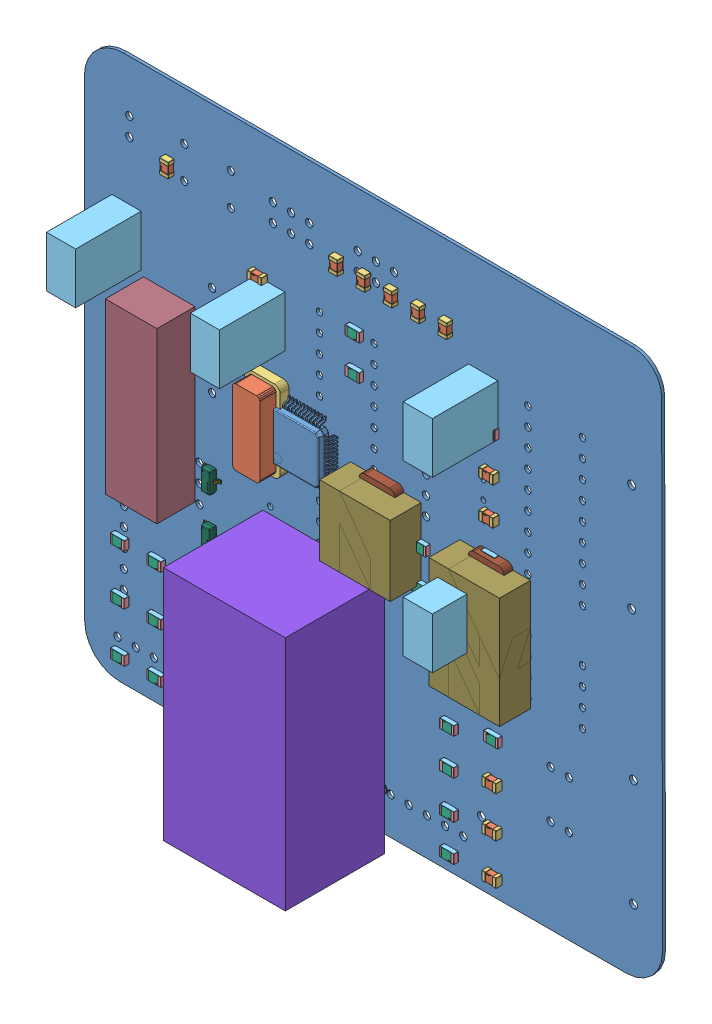
SolidWorks assembly VTM Ethernet Module.step, configuration Default. Lengths in mm.
Overall size (80.69 78.46 18.97).
296 component instances, 25 part files, 0 mates.
Components (placement in the parent):
- Board.step-1: Board.step [Default] at origin size (80.69 76.24 0.41)
  - Open CASCADE STEP translator 7.5 1.1.1.step-1: Open CASCADE STEP translator 7.5 1.1.1.step [Default] at (0 0 -0.4115) size (80.69 76.24 0.41)
- Y1.step-1: Y1.step [Default] at origin size (5 11.35 3.5)
  - 6024891824.step-1: 6024891824.step [Default] at (26.035 42.291 0) size (3.8 10.5 3.5)
    - Extruded.step-1: Extruded.step [Default] at origin size (3.8 10.5 3.5)
  - 6024891904.step-1: 6024891904.step [Default] at (26.035 42.291 0) size (5 11.35 1.25)
    - Extruded-0.step-1: Extruded-0.step [Default] at origin size (5 11.35 1.25)
- RY.step-1: RY.step [Default] at origin size (2 1.25 0.65)
  - Res_TE_Connectivity_CPF0805B66R5E1_eec.step-1: Res_TE_Connectivity_CPF0805B66R5E1_eec.step [Default] at (51.169 17.907 0) size (2 1.25 0.65)
    - 1.step-1: 1.step [Default] at origin size (2 1.25 0.65)
    - 2.step-1: 2.step [Default] at origin size (1.92 1.25 0.61)
    - 3.step-1: 3.step [Default] at origin size (1.3 1.25 0.04)
    - TE connectivity Logo 1 (2).step-1: TE connectivity Logo 1 (2).step [Default] at (5.4285 0.313 0.551) x (-1 0 0) z (0 0 1) size (0.37 0.13 0.11)
- RLL5.step-1: RLL5.step [Default] at origin size (2 1.25 0.65)
  - Res_TE_Connectivity_CPF0805B66R5E1_eec.step-1: Res_TE_Connectivity_CPF0805B66R5E1_eec.step [Default] at (10.287 3.368 0) x (-1 0 0) z (0 0 1) size (2 1.25 0.65)
    - 1.step-1: 1.step [Default] at origin size (2 1.25 0.65)
    - 2.step-1: 2.step [Default] at origin size (1.92 1.25 0.61)
    - 3.step-1: 3.step [Default] at origin size (1.3 1.25 0.04)
    - TE connectivity Logo 1 (2).step-1: TE connectivity Logo 1 (2).step [Default] at (5.4285 0.313 0.551) x (-1 0 0) z (0 0 1) size (0.37 0.13 0.11)
- RLL4.step-1: RLL4.step [Default] at origin size (2 1.25 0.65)
  - Res_TE_Connectivity_CPF0805B66R5E1_eec.step-1: Res_TE_Connectivity_CPF0805B66R5E1_eec.step [Default] at (10.287 10.287 0) x (-1 0 0) z (0 0 1) size (2 1.25 0.65)
    - 1.step-1: 1.step [Default] at origin size (2 1.25 0.65)
    - 2.step-1: 2.step [Default] at origin size (1.92 1.25 0.61)
    - 3.step-1: 3.step [Default] at origin size (1.3 1.25 0.04)
    - TE connectivity Logo 1 (2).step-1: TE connectivity Logo 1 (2).step [Default] at (5.4285 0.313 0.551) x (-1 0 0) z (0 0 1) size (0.37 0.13 0.11)
- RLL3.step-1: RLL3.step [Default] at origin size (2 1.25 0.65)
  - Res_TE_Connectivity_CPF0805B66R5E1_eec.step-1: Res_TE_Connectivity_CPF0805B66R5E1_eec.step [Default] at (10.287 17.272 0) x (-1 0 0) z (0 0 1) size (2 1.25 0.65)
    - 1.step-1: 1.step [Default] at origin size (2 1.25 0.65)
    - 2.step-1: 2.step [Default] at origin size (1.92 1.25 0.61)
    - 3.step-1: 3.step [Default] at origin size (1.3 1.25 0.04)
    - TE connectivity Logo 1 (2).step-1: TE connectivity Logo 1 (2).step [Default] at (5.4285 0.313 0.551) x (-1 0 0) z (0 0 1) size (0.37 0.13 0.11)
- RLL2.step-1: RLL2.step [Default] at origin size (2 1.25 0.65)
  - Res_TE_Connectivity_CPF0805B66R5E1_eec.step-1: Res_TE_Connectivity_CPF0805B66R5E1_eec.step [Default] at (10.287 24.257 0) x (-1 0 0) z (0 0 1) size (2 1.25 0.65)
    - 1.step-1: 1.step [Default] at origin size (2 1.25 0.65)
    - 2.step-1: 2.step [Default] at origin size (1.92 1.25 0.61)
    - 3.step-1: 3.step [Default] at origin size (1.3 1.25 0.04)
    - TE connectivity Logo 1 (2).step-1: TE connectivity Logo 1 (2).step [Default] at (5.4285 0.313 0.551) x (-1 0 0) z (0 0 1) size (0.37 0.13 0.11)
- RLL1.step-1: RLL1.step [Default] at origin size (2 1.25 0.65)
  - Res_TE_Connectivity_CPF0805B66R5E1_eec.step-1: Res_TE_Connectivity_CPF0805B66R5E1_eec.step [Default] at (10.287 31.181 0) x (-1 0 0) z (0 0 1) size (2 1.25 0.65)
    - 1.step-1: 1.step [Default] at origin size (2 1.25 0.65)
    - 2.step-1: 2.step [Default] at origin size (1.92 1.25 0.61)
    - 3.step-1: 3.step [Default] at origin size (1.3 1.25 0.04)
    - TE connectivity Logo 1 (2).step-1: TE connectivity Logo 1 (2).step [Default] at (5.4285 0.313 0.551) x (-1 0 0) z (0 0 1) size (0.37 0.13 0.11)
- RLH5.step-1: RLH5.step [Default] at origin size (2 1.25 0.65)
  - Res_TE_Connectivity_CPF0805B66R5E1_eec.step-1: Res_TE_Connectivity_CPF0805B66R5E1_eec.step [Default] at (5.191 3.368 0) x (-1 0 0) z (0 0 1) size (2 1.25 0.65)
    - 1.step-1: 1.step [Default] at origin size (2 1.25 0.65)
    - 2.step-1: 2.step [Default] at origin size (1.92 1.25 0.61)
    - 3.step-1: 3.step [Default] at origin size (1.3 1.25 0.04)
    - TE connectivity Logo 1 (2).step-1: TE connectivity Logo 1 (2).step [Default] at (5.4285 0.313 0.551) x (-1 0 0) z (0 0 1) size (0.37 0.13 0.11)
- RLH4.step-1: RLH4.step [Default] at origin size (2 1.25 0.65)
  - Res_TE_Connectivity_CPF0805B66R5E1_eec.step-1: Res_TE_Connectivity_CPF0805B66R5E1_eec.step [Default] at (5.191 10.287 0) x (-1 0 0) z (0 0 1) size (2 1.25 0.65)
    - 1.step-1: 1.step [Default] at origin size (2 1.25 0.65)
    - 2.step-1: 2.step [Default] at origin size (1.92 1.25 0.61)
    - 3.step-1: 3.step [Default] at origin size (1.3 1.25 0.04)
    - TE connectivity Logo 1 (2).step-1: TE connectivity Logo 1 (2).step [Default] at (5.4285 0.313 0.551) x (-1 0 0) z (0 0 1) size (0.37 0.13 0.11)
- RLH3.step-1: RLH3.step [Default] at origin size (2 1.25 0.65)
  - Res_TE_Connectivity_CPF0805B66R5E1_eec.step-1: Res_TE_Connectivity_CPF0805B66R5E1_eec.step [Default] at (5.191 17.272 0) x (-1 0 0) z (0 0 1) size (2 1.25 0.65)
    - 1.step-1: 1.step [Default] at origin size (2 1.25 0.65)
    - 2.step-1: 2.step [Default] at origin size (1.92 1.25 0.61)
    - 3.step-1: 3.step [Default] at origin size (1.3 1.25 0.04)
    - TE connectivity Logo 1 (2).step-1: TE connectivity Logo 1 (2).step [Default] at (5.4285 0.313 0.551) x (-1 0 0) z (0 0 1) size (0.37 0.13 0.11)
- RLH2.step-1: RLH2.step [Default] at origin size (2 1.25 0.65)
  - Res_TE_Connectivity_CPF0805B66R5E1_eec.step-1: Res_TE_Connectivity_CPF0805B66R5E1_eec.step [Default] at (5.191 24.257 0) x (-1 0 0) z (0 0 1) size (2 1.25 0.65)
    - 1.step-1: 1.step [Default] at origin size (2 1.25 0.65)
    - 2.step-1: 2.step [Default] at origin size (1.92 1.25 0.61)
    - 3.step-1: 3.step [Default] at origin size (1.3 1.25 0.04)
    - TE connectivity Logo 1 (2).step-1: TE connectivity Logo 1 (2).step [Default] at (5.4285 0.313 0.551) x (-1 0 0) z (0 0 1) size (0.37 0.13 0.11)
- RLH1.step-1: RLH1.step [Default] at origin size (2 1.25 0.65)
  - Res_TE_Connectivity_CPF0805B66R5E1_eec.step-1: Res_TE_Connectivity_CPF0805B66R5E1_eec.step [Default] at (5.191 31.181 0) x (-1 0 0) z (0 0 1) size (2 1.25 0.65)
    - 1.step-1: 1.step [Default] at origin size (2 1.25 0.65)
    - 2.step-1: 2.step [Default] at origin size (1.92 1.25 0.61)
    - 3.step-1: 3.step [Default] at origin size (1.3 1.25 0.04)
    - TE connectivity Logo 1 (2).step-1: TE connectivity Logo 1 (2).step [Default] at (5.4285 0.313 0.551) x (-1 0 0) z (0 0 1) size (0.37 0.13 0.11)
- RJ45.step-1: RJ45.step [Default] at origin size (17.5 33.02 18.97)
  - 6024909664.step-1: 6024909664.step [Default] at (38.539 23.881 0) x (1 0 0) z (0 0 1) size (17.5 33.02 18.97)
    - Body.step-1: Body.step [Default] at (0 0 0.1) size (17 33.02 13.87)
    - Lugs.step-1: Lugs.step [Default] at origin size (15.3 2.6 1.8)
    - Leads.step-1: Leads.step [Default] at origin size (17.5 24.59 5.1)
- RG.step-1: RG.step [Default] at origin size (2 1.25 0.65)
  - Res_TE_Connectivity_CPF0805B66R5E1_eec.step-1: Res_TE_Connectivity_CPF0805B66R5E1_eec.step [Default] at (51.153 12.827 0) size (2 1.25 0.65)
    - 1.step-1: 1.step [Default] at origin size (2 1.25 0.65)
    - 2.step-1: 2.step [Default] at origin size (1.92 1.25 0.61)
    - 3.step-1: 3.step [Default] at origin size (1.3 1.25 0.04)
    - TE connectivity Logo 1 (2).step-1: TE connectivity Logo 1 (2).step [Default] at (5.4285 0.313 0.551) x (-1 0 0) z (0 0 1) size (0.37 0.13 0.11)
- R_MH4.step-1: R_MH4.step [Default] at origin size (2 1.25 0.65)
  - Res_TE_Connectivity_CPF0805B66R5E1_eec.step-1: Res_TE_Connectivity_CPF0805B66R5E1_eec.step [Default] at (51.169 7.493 0) x (-1 0 0) z (0 0 1) size (2 1.25 0.65)
    - 1.step-1: 1.step [Default] at origin size (2 1.25 0.65)
    - 2.step-1: 2.step [Default] at origin size (1.92 1.25 0.61)
    - 3.step-1: 3.step [Default] at origin size (1.3 1.25 0.04)
    - TE connectivity Logo 1 (2).step-1: TE connectivity Logo 1 (2).step [Default] at (5.4285 0.313 0.551) x (-1 0 0) z (0 0 1) size (0.37 0.13 0.11)
- R_MH3.step-1: R_MH3.step [Default] at origin size (2 1.25 0.65)
  - Res_TE_Connectivity_CPF0805B66R5E1_eec.step-1: Res_TE_Connectivity_CPF0805B66R5E1_eec.step [Default] at (51.169 2.413 0) x (-1 0 0) z (0 0 1) size (2 1.25 0.65)
    - 1.step-1: 1.step [Default] at origin size (2 1.25 0.65)
    - 2.step-1: 2.step [Default] at origin size (1.92 1.25 0.61)
    - 3.step-1: 3.step [Default] at origin size (1.3 1.25 0.04)
    - TE connectivity Logo 1 (2).step-1: TE connectivity Logo 1 (2).step [Default] at (5.4285 0.313 0.551) x (-1 0 0) z (0 0 1) size (0.37 0.13 0.11)
- R15.step-1: R15.step [Default] at origin size (2 1.25 0.65)
  - Res_TE_Connectivity_CPF0805B66R5E1_eec.step-1: Res_TE_Connectivity_CPF0805B66R5E1_eec.step [Default] at (56.841 41.021 0) size (2 1.25 0.65)
    - 1.step-1: 1.step [Default] at origin size (2 1.25 0.65)
    - 2.step-1: 2.step [Default] at origin size (1.92 1.25 0.61)
    - 3.step-1: 3.step [Default] at origin size (1.3 1.25 0.04)
    - TE connectivity Logo 1 (2).step-1: TE connectivity Logo 1 (2).step [Default] at (5.4285 0.313 0.551) x (-1 0 0) z (0 0 1) size (0.37 0.13 0.11)
- R14.step-1: R14.step [Default] at origin size (2 1.25 0.65)
  - Res_TE_Connectivity_CPF0805B66R5E1_eec.step-1: Res_TE_Connectivity_CPF0805B66R5E1_eec.step [Default] at (37.973 58.828 0) x (-1 0 0) z (0 0 1) size (2 1.25 0.65)
    - 1.step-1: 1.step [Default] at origin size (2 1.25 0.65)
    - 2.step-1: 2.step [Default] at origin size (1.92 1.25 0.61)
    - 3.step-1: 3.step [Default] at origin size (1.3 1.25 0.04)
    - TE connectivity Logo 1 (2).step-1: TE connectivity Logo 1 (2).step [Default] at (5.4285 0.313 0.551) x (-1 0 0) z (0 0 1) size (0.37 0.13 0.11)
- R13.step-1: R13.step [Default] at origin size (2 1.25 0.65)
  - Res_TE_Connectivity_CPF0805B66R5E1_eec.step-1: Res_TE_Connectivity_CPF0805B66R5E1_eec.step [Default] at (37.973 53.948 0) x (1 0 0) z (0 0 1) size (2 1.25 0.65)
    - 1.step-1: 1.step [Default] at origin size (2 1.25 0.65)
    - 2.step-1: 2.step [Default] at origin size (1.92 1.25 0.61)
    - 3.step-1: 3.step [Default] at origin size (1.3 1.25 0.04)
    - TE connectivity Logo 1 (2).step-1: TE connectivity Logo 1 (2).step [Default] at (5.4285 0.313 0.551) x (-1 0 0) z (0 0 1) size (0.37 0.13 0.11)
- R12.step-1: R12.step [Default] at origin size (2 1.25 0.65)
  - Res_TE_Connectivity_CPF0805B66R5E1_eec.step-1: Res_TE_Connectivity_CPF0805B66R5E1_eec.step [Default] at (57.277 19.431 0) size (2 1.25 0.65)
    - 1.step-1: 1.step [Default] at origin size (2 1.25 0.65)
    - 2.step-1: 2.step [Default] at origin size (1.92 1.25 0.61)
    - 3.step-1: 3.step [Default] at origin size (1.3 1.25 0.04)
    - TE connectivity Logo 1 (2).step-1: TE connectivity Logo 1 (2).step [Default] at (5.4285 0.313 0.551) x (-1 0 0) z (0 0 1) size (0.37 0.13 0.11)
- R11.step-1: R11.step [Default] at origin size (2 1.25 0.65)
  - Res_TE_Connectivity_CPF0805B66R5E1_eec.step-1: Res_TE_Connectivity_CPF0805B66R5E1_eec.step [Default] at (57.277 24.511 0) size (2 1.25 0.65)
    - 1.step-1: 1.step [Default] at origin size (2 1.25 0.65)
    - 2.step-1: 2.step [Default] at origin size (1.92 1.25 0.61)
    - 3.step-1: 3.step [Default] at origin size (1.3 1.25 0.04)
    - TE connectivity Logo 1 (2).step-1: TE connectivity Logo 1 (2).step [Default] at (5.4285 0.313 0.551) x (-1 0 0) z (0 0 1) size (0.37 0.13 0.11)
- R10.step-1: R10.step [Default] at origin size (9.85 11.35 4.32)
  - 6024890784.step-1: 6024890784.step [Default] at (57.277 30.226 0) size (5 11.35 1.25)
    - Extruded-1.step-1: Extruded-1.step [Default] at origin size (5 11.35 1.25)
  - 6024891024.step-1: 6024891024.step [Default] at (55.902 30.226 0) size (7.1 9.8 4.32)
    - Extruded-2.step-1: Extruded-2.step [Default] at origin size (7.1 9.8 4.32)
  - 6024891024.step-2: 6024891024.step [Default] at (58.652 30.226 0) size (7.1 9.8 4.32)
    - Extruded-2.step-1: Extruded-2.step [Default] at origin size (7.1 9.8 4.32)
- R9.step-1: R9.step [Default] at origin size (9.85 11.35 4.32)
  - 6024891024.step-1: 6024891024.step [Default] at (58.652 35.941 0) size (7.1 9.8 4.32)
    - Extruded-2.step-1: Extruded-2.step [Default] at origin size (7.1 9.8 4.32)
  - 6024891024.step-2: 6024891024.step [Default] at (55.902 35.941 0) size (7.1 9.8 4.32)
    - Extruded-2.step-1: Extruded-2.step [Default] at origin size (7.1 9.8 4.32)
  - 6024890784.step-1: 6024890784.step [Default] at (57.277 35.941 0) size (5 11.35 1.25)
    - Extruded-1.step-1: Extruded-1.step [Default] at origin size (5 11.35 1.25)
- R8.step-1: R8.step [Default] at origin size (7.2 23.6 5.33)
  - 6024888544.step-1: 6024888544.step [Default] at (11.811 38.735 0) size (7.2 23.6 5.33)
    - Extruded-3.step-1: Extruded-3.step [Default] at origin size (7.2 23.6 5.33)
  - 6024888384.step-1: 6024888384.step [Default] at (11.811 40.11 0) size (1.65 0.5 0.7)
    - Extruded-4.step-1: Extruded-4.step [Default] at origin size (1.65 0.5 0.7)
  - 6024888384.step-2: 6024888384.step [Default] at (11.811 37.36 0) size (1.65 0.5 0.7)
    - Extruded-4.step-1: Extruded-4.step [Default] at origin size (1.65 0.5 0.7)
- R7.step-1: R7.step [Default] at origin size (9.85 11.35 4.32)
  - 6024890784.step-1: 6024890784.step [Default] at (42.037 37.719 0) size (5 11.35 1.25)
    - Extruded-1.step-1: Extruded-1.step [Default] at origin size (5 11.35 1.25)
  - 6024891024.step-1: 6024891024.step [Default] at (40.662 37.719 0) size (7.1 9.8 4.32)
    - Extruded-2.step-1: Extruded-2.step [Default] at origin size (7.1 9.8 4.32)
  - 6024891024.step-2: 6024891024.step [Default] at (43.412 37.719 0) size (7.1 9.8 4.32)
    - Extruded-2.step-1: Extruded-2.step [Default] at origin size (7.1 9.8 4.32)
- R6.step-1: R6.step [Default] at origin size (2 1.25 0.65)
  - Res_TE_Connectivity_CPF0805B66R5E1_eec.step-1: Res_TE_Connectivity_CPF0805B66R5E1_eec.step [Default] at (56.841 56.388 0) size (2 1.25 0.65)
    - 1.step-1: 1.step [Default] at origin size (2 1.25 0.65)
    - 2.step-1: 2.step [Default] at origin size (1.92 1.25 0.61)
    - 3.step-1: 3.step [Default] at origin size (1.3 1.25 0.04)
    - TE connectivity Logo 1 (2).step-1: TE connectivity Logo 1 (2).step [Default] at (5.4285 0.313 0.551) x (-1 0 0) z (0 0 1) size (0.37 0.13 0.11)
- R5.step-1: R5.step [Default] at origin size (2 1.25 0.65)
  - Res_TE_Connectivity_CPF0805B66R5E1_eec.step-1: Res_TE_Connectivity_CPF0805B66R5E1_eec.step [Default] at (47.244 37.592 0) size (2 1.25 0.65)
    - 1.step-1: 1.step [Default] at origin size (2 1.25 0.65)
    - 2.step-1: 2.step [Default] at origin size (1.92 1.25 0.61)
    - 3.step-1: 3.step [Default] at origin size (1.3 1.25 0.04)
    - TE connectivity Logo 1 (2).step-1: TE connectivity Logo 1 (2).step [Default] at (5.4285 0.313 0.551) x (-1 0 0) z (0 0 1) size (0.37 0.13 0.11)
- R4.step-1: R4.step [Default] at origin size (2 1.25 0.65)
  - Res_TE_Connectivity_CPF0805B66R5E1_eec.step-1: Res_TE_Connectivity_CPF0805B66R5E1_eec.step [Default] at (51.169 22.987 0) size (2 1.25 0.65)
    - 1.step-1: 1.step [Default] at origin size (2 1.25 0.65)
    - 2.step-1: 2.step [Default] at origin size (1.92 1.25 0.61)
    - 3.step-1: 3.step [Default] at origin size (1.3 1.25 0.04)
    - TE connectivity Logo 1 (2).step-1: TE connectivity Logo 1 (2).step [Default] at (5.4285 0.313 0.551) x (-1 0 0) z (0 0 1) size (0.37 0.13 0.11)
- R3.step-1: R3.step [Default] at origin size (2 1.25 0.65)
  - Res_TE_Connectivity_CPF0805B66R5E1_eec.step-1: Res_TE_Connectivity_CPF0805B66R5E1_eec.step [Default] at (47.117 32.639 0) x (-1 0 0) z (0 0 1) size (2 1.25 0.65)
    - 1.step-1: 1.step [Default] at origin size (2 1.25 0.65)
    - 2.step-1: 2.step [Default] at origin size (1.92 1.25 0.61)
    - 3.step-1: 3.step [Default] at origin size (1.3 1.25 0.04)
    - TE connectivity Logo 1 (2).step-1: TE connectivity Logo 1 (2).step [Default] at (5.4285 0.313 0.551) x (-1 0 0) z (0 0 1) size (0.37 0.13 0.11)
- R2.step-1: R2.step [Default] at origin size (2 1.25 0.65)
  - Res_TE_Connectivity_CPF0805B66R5E1_eec.step-1: Res_TE_Connectivity_CPF0805B66R5E1_eec.step [Default] at (42.037 32.512 0) size (2 1.25 0.65)
    - 1.step-1: 1.step [Default] at origin size (2 1.25 0.65)
    - 2.step-1: 2.step [Default] at origin size (1.92 1.25 0.61)
    - 3.step-1: 3.step [Default] at origin size (1.3 1.25 0.04)
    - TE connectivity Logo 1 (2).step-1: TE connectivity Logo 1 (2).step [Default] at (5.4285 0.313 0.551) x (-1 0 0) z (0 0 1) size (0.37 0.13 0.11)
- R1.step-1: R1.step [Default] at origin size (1.25 2 0.65)
  - Res_TE_Connectivity_CPF0805B66R5E1_eec.step-1: Res_TE_Connectivity_CPF0805B66R5E1_eec.step [Default] at (7.366 38.862 0) x (0 -1 0) z (0 0 1) size (2 1.25 0.65)
    - 1.step-1: 1.step [Default] at origin size (2 1.25 0.65)
    - 2.step-1: 2.step [Default] at origin size (1.92 1.25 0.61)
    - 3.step-1: 3.step [Default] at origin size (1.3 1.25 0.04)
    - TE connectivity Logo 1 (2).step-1: TE connectivity Logo 1 (2).step [Default] at (5.4285 0.313 0.551) x (-1 0 0) z (0 0 1) size (0.37 0.13 0.11)
- Q1.step-1: Q1.step [Default] at origin size (2.4 2.9 1.11)
  - IC_ON_Semiconductor_NUD3112LT1G_eec.step-1: IC_ON_Semiconductor_NUD3112LT1G_eec.step [Default] at (17.919 31.181 0) size (2.4 2.9 1.11)
    - 1-5.step-1: 1-5.step [Default] at (0 0 0.1) x (0 1 0) z (0 0 1) size (2.9 1.3 1.01)
    - 2-6.step-1: 2-6.step [Default] x (-1 0 0) z (0 1 0) size (2.4 0.68 2.34)
    - ON Semi Logo - withoutPN.step-1: ON Semi Logo - withoutPN.step [Default] at (-0.2581 -0.9018 1.011) x (-1 0 0) z (0 0 1) size (0.19 0.19 0.1)
    - ON Semi Logo - withoutPN - Copy.step-1: ON Semi Logo - withoutPN - Copy.step [Default] at (-0.2645 -0.8914 1.011) x (-1 0 0) z (0 0 1) size (0.83 2.45 0.1)
- Q5.step-1: Q5.step [Default] at origin size (2.4 2.9 1.11)
  - IC_ON_Semiconductor_NUD3112LT1G_eec.step-1: IC_ON_Semiconductor_NUD3112LT1G_eec.step [Default] at (17.9402 3.368 0) size (2.4 2.9 1.11)
    - 1-5.step-1: 1-5.step [Default] at (0 0 0.1) x (0 1 0) z (0 0 1) size (2.9 1.3 1.01)
    - 2-6.step-1: 2-6.step [Default] x (-1 0 0) z (0 1 0) size (2.4 0.68 2.34)
    - ON Semi Logo - withoutPN.step-1: ON Semi Logo - withoutPN.step [Default] at (-0.2581 -0.9018 1.011) x (-1 0 0) z (0 0 1) size (0.19 0.19 0.1)
    - ON Semi Logo - withoutPN - Copy.step-1: ON Semi Logo - withoutPN - Copy.step [Default] at (-0.2645 -0.8914 1.011) x (-1 0 0) z (0 0 1) size (0.83 2.45 0.1)
- Q3.step-1: Q3.step [Default] at origin size (2.4 2.9 1.11)
  - IC_ON_Semiconductor_NUD3112LT1G_eec.step-1: IC_ON_Semiconductor_NUD3112LT1G_eec.step [Default] at (17.919 17.272 0) size (2.4 2.9 1.11)
    - 1-5.step-1: 1-5.step [Default] at (0 0 0.1) x (0 1 0) z (0 0 1) size (2.9 1.3 1.01)
    - 2-6.step-1: 2-6.step [Default] x (-1 0 0) z (0 1 0) size (2.4 0.68 2.34)
    - ON Semi Logo - withoutPN.step-1: ON Semi Logo - withoutPN.step [Default] at (-0.2581 -0.9018 1.011) x (-1 0 0) z (0 0 1) size (0.19 0.19 0.1)
    - ON Semi Logo - withoutPN - Copy.step-1: ON Semi Logo - withoutPN - Copy.step [Default] at (-0.2645 -0.8914 1.011) x (-1 0 0) z (0 0 1) size (0.83 2.45 0.1)
- Q4.step-1: Q4.step [Default] at origin size (2.4 2.9 1.11)
  - IC_ON_Semiconductor_NUD3112LT1G_eec.step-1: IC_ON_Semiconductor_NUD3112LT1G_eec.step [Default] at (17.919 10.287 0) x (1 0 0) z (0 0 1) size (2.4 2.9 1.11)
    - 1-5.step-1: 1-5.step [Default] at (0 0 0.1) x (0 1 0) z (0 0 1) size (2.9 1.3 1.01)
    - 2-6.step-1: 2-6.step [Default] x (-1 0 0) z (0 1 0) size (2.4 0.68 2.34)
    - ON Semi Logo - withoutPN.step-1: ON Semi Logo - withoutPN.step [Default] at (-0.2581 -0.9018 1.011) x (-1 0 0) z (0 0 1) size (0.19 0.19 0.1)
    - ON Semi Logo - withoutPN - Copy.step-1: ON Semi Logo - withoutPN - Copy.step [Default] at (-0.2645 -0.8914 1.011) x (-1 0 0) z (0 0 1) size (0.83 2.45 0.1)
- Q2.step-1: Q2.step [Default] at origin size (2.4 2.9 1.11)
  - IC_ON_Semiconductor_NUD3112LT1G_eec.step-1: IC_ON_Semiconductor_NUD3112LT1G_eec.step [Default] at (17.919 24.257 0) size (2.4 2.9 1.11)
    - 1-5.step-1: 1-5.step [Default] at (0 0 0.1) x (0 1 0) z (0 0 1) size (2.9 1.3 1.01)
    - 2-6.step-1: 2-6.step [Default] x (-1 0 0) z (0 1 0) size (2.4 0.68 2.34)
    - ON Semi Logo - withoutPN.step-1: ON Semi Logo - withoutPN.step [Default] at (-0.2581 -0.9018 1.011) x (-1 0 0) z (0 0 1) size (0.19 0.19 0.1)
    - ON Semi Logo - withoutPN - Copy.step-1: ON Semi Logo - withoutPN - Copy.step [Default] at (-0.2645 -0.8914 1.011) x (-1 0 0) z (0 0 1) size (0.83 2.45 0.1)
- FB1.step-1: FB1.step [Default] at origin size (33.02 17 13.87)
  - FBead_Murata_BLM18EG221SN1D_eec.step-1: FBead_Murata_BLM18EG221SN1D_eec.step [Default] at (25.61 65.924 0) x (0 1 0) z (0 0 1) size (17 33.02 13.87) (hidden)
    - Body.step-1: Body.step [Default] x (-1 0 0) z (0 0 1) size (17 33.02 13.87)
    - side.step-1: side.step [Default] at (-0.5 0.4917 0) x (-1 0 0) z (0 0 1) size (0.4 0.8 0.95)
    - side.step-2: side.step [Default] at (0.5 0.4917 0.95) x (1 0 0) z (0 0 -1) size (0.4 0.8 0.95)
    - Murata.step-1: Murata.step [Default] at (-0.8876 -0.696 0.892) size (0.61 0.14 0.03)
- W5500.step-1: W5500.step [Default] at origin size (9 9 1.6)
  - 6024908304.step-1: 6024908304.step [Default] at (30.861 41.91 0) x (0 1 0) z (1 0 0) size (9 1.6 9)
- C18.step-1: C18.step [Default] at origin size (2 1.25 0.88)
  - Cap_KEMET_C0805C472J3HAC_eec.step-1: Cap_KEMET_C0805C472J3HAC_eec.step [Default] at (56.841 51.181 0) size (1 1.15 0.78)
  - Cap_KEMET_C0805C472J3HAC_eec-7.step-1: Cap_KEMET_C0805C472J3HAC_eec-7.step [Default] at (56.841 51.181 0) size (2 1.25 0.88)
  - Cap_KEMET_C0805C472J3HAC_eec-8.step-1: Cap_KEMET_C0805C472J3HAC_eec-8.step [Default] at (56.841 51.181 0) size (0.59 0.12 0)
- C17.step-1: C17.step [Default] at origin size (2 1.25 0.88)
  - Cap_KEMET_C0805C472J3HAC_eec.step-1: Cap_KEMET_C0805C472J3HAC_eec.step [Default] at (56.841 45.974 0) size (1 1.15 0.78)
  - Cap_KEMET_C0805C472J3HAC_eec-7.step-1: Cap_KEMET_C0805C472J3HAC_eec-7.step [Default] at (56.841 45.974 0) size (2 1.25 0.88)
  - Cap_KEMET_C0805C472J3HAC_eec-8.step-1: Cap_KEMET_C0805C472J3HAC_eec-8.step [Default] at (56.841 45.974 0) size (0.59 0.12 0)
- C16.step-1: C16.step [Default] at origin size (2 1.25 0.88)
  - Cap_KEMET_C0805C472J3HAC_eec.step-1: Cap_KEMET_C0805C472J3HAC_eec.step [Default] at (24.523 58.828 0) size (1 1.15 0.78)
  - Cap_KEMET_C0805C472J3HAC_eec-7.step-1: Cap_KEMET_C0805C472J3HAC_eec-7.step [Default] at (24.523 58.828 0) size (2 1.25 0.88)
  - Cap_KEMET_C0805C472J3HAC_eec-8.step-1: Cap_KEMET_C0805C472J3HAC_eec-8.step [Default] at (24.523 58.828 0) size (0.59 0.12 0)
- C15.step-1: C15.step [Default] at origin size (2 1.25 0.88)
  - Cap_KEMET_C0805C472J3HAC_eec.step-1: Cap_KEMET_C0805C472J3HAC_eec.step [Default] at (24.523 53.948 0) size (1 1.15 0.78)
  - Cap_KEMET_C0805C472J3HAC_eec-7.step-1: Cap_KEMET_C0805C472J3HAC_eec-7.step [Default] at (24.523 53.948 0) size (2 1.25 0.88)
  - Cap_KEMET_C0805C472J3HAC_eec-8.step-1: Cap_KEMET_C0805C472J3HAC_eec-8.step [Default] at (24.523 53.948 0) size (0.59 0.12 0)
- C14.step-1: C14.step [Default] at origin size (2 1.25 0.88)
  - Cap_KEMET_C0805C472J3HAC_eec.step-1: Cap_KEMET_C0805C472J3HAC_eec.step [Default] at (57.277 2.667 0) size (1 1.15 0.78)
  - Cap_KEMET_C0805C472J3HAC_eec-7.step-1: Cap_KEMET_C0805C472J3HAC_eec-7.step [Default] at (57.277 2.667 0) size (2 1.25 0.88)
  - Cap_KEMET_C0805C472J3HAC_eec-8.step-1: Cap_KEMET_C0805C472J3HAC_eec-8.step [Default] at (57.277 2.667 0) size (0.59 0.12 0)
- C13.step-1: C13.step [Default] at origin size (2 1.25 0.88)
  - Cap_KEMET_C0805C472J3HAC_eec.step-1: Cap_KEMET_C0805C472J3HAC_eec.step [Default] at (57.277 8.382 0) size (1 1.15 0.78)
  - Cap_KEMET_C0805C472J3HAC_eec-7.step-1: Cap_KEMET_C0805C472J3HAC_eec-7.step [Default] at (57.277 8.382 0) size (2 1.25 0.88)
  - Cap_KEMET_C0805C472J3HAC_eec-8.step-1: Cap_KEMET_C0805C472J3HAC_eec-8.step [Default] at (57.277 8.382 0) size (0.59 0.12 0)
- C12.step-1: C12.step [Default] at origin size (2 1.25 0.88)
  - Cap_KEMET_C0805C472J3HAC_eec.step-1: Cap_KEMET_C0805C472J3HAC_eec.step [Default] at (57.277 14.097 0) size (1 1.15 0.78)
  - Cap_KEMET_C0805C472J3HAC_eec-7.step-1: Cap_KEMET_C0805C472J3HAC_eec-7.step [Default] at (57.277 14.097 0) size (2 1.25 0.88)
  - Cap_KEMET_C0805C472J3HAC_eec-8.step-1: Cap_KEMET_C0805C472J3HAC_eec-8.step [Default] at (57.277 14.097 0) size (0.59 0.12 0)
- C11.step-1: C11.step [Default] at origin size (2 1.25 0.88)
  - Cap_KEMET_C0805C472J3HAC_eec.step-1: Cap_KEMET_C0805C472J3HAC_eec.step [Default] at (51.042 28.702 0) size (1 1.15 0.78)
  - Cap_KEMET_C0805C472J3HAC_eec-7.step-1: Cap_KEMET_C0805C472J3HAC_eec-7.step [Default] at (51.042 28.702 0) size (2 1.25 0.88)
  - Cap_KEMET_C0805C472J3HAC_eec-8.step-1: Cap_KEMET_C0805C472J3HAC_eec-8.step [Default] at (51.042 28.702 0) size (0.59 0.12 0)
- C10.step-1: C10.step [Default] at origin size (1.25 2 0.88)
  - Cap_KEMET_C0805C472J3HAC_eec.step-1: Cap_KEMET_C0805C472J3HAC_eec.step [Default] at (50.756 65.924 0) x (0 1 0) z (0 0 1) size (1 1.15 0.78)
  - Cap_KEMET_C0805C472J3HAC_eec-7.step-1: Cap_KEMET_C0805C472J3HAC_eec-7.step [Default] at (50.756 65.924 0) x (0 1 0) z (0 0 1) size (2 1.25 0.88)
  - Cap_KEMET_C0805C472J3HAC_eec-8.step-1: Cap_KEMET_C0805C472J3HAC_eec-8.step [Default] at (50.756 65.924 0) x (0 1 0) z (0 0 1) size (0.59 0.12 0)
- C9.step-1: C9.step [Default] at origin size (1.25 2 0.88)
  - Cap_KEMET_C0805C472J3HAC_eec.step-1: Cap_KEMET_C0805C472J3HAC_eec.step [Default] at (46.946 65.924 0) x (0 1 0) z (0 0 1) size (1 1.15 0.78)
  - Cap_KEMET_C0805C472J3HAC_eec-7.step-1: Cap_KEMET_C0805C472J3HAC_eec-7.step [Default] at (46.946 65.924 0) x (0 1 0) z (0 0 1) size (2 1.25 0.88)
  - Cap_KEMET_C0805C472J3HAC_eec-8.step-1: Cap_KEMET_C0805C472J3HAC_eec-8.step [Default] at (46.946 65.924 0) x (0 1 0) z (0 0 1) size (0.59 0.12 0)
- C8.step-1: C8.step [Default] at origin size (1.25 2 0.88)
  - Cap_KEMET_C0805C472J3HAC_eec.step-1: Cap_KEMET_C0805C472J3HAC_eec.step [Default] at (43.136 65.924 0) x (0 1 0) z (0 0 1) size (1 1.15 0.78)
  - Cap_KEMET_C0805C472J3HAC_eec-7.step-1: Cap_KEMET_C0805C472J3HAC_eec-7.step [Default] at (43.136 65.924 0) x (0 1 0) z (0 0 1) size (2 1.25 0.88)
  - Cap_KEMET_C0805C472J3HAC_eec-8.step-1: Cap_KEMET_C0805C472J3HAC_eec-8.step [Default] at (43.136 65.924 0) x (0 1 0) z (0 0 1) size (0.59 0.12 0)
- C7.step-1: C7.step [Default] at origin size (1.25 2 0.88)
  - Cap_KEMET_C0805C472J3HAC_eec.step-1: Cap_KEMET_C0805C472J3HAC_eec.step [Default] at (39.326 65.924 0) x (0 1 0) z (0 0 1) size (1 1.15 0.78)
  - Cap_KEMET_C0805C472J3HAC_eec-7.step-1: Cap_KEMET_C0805C472J3HAC_eec-7.step [Default] at (39.326 65.924 0) x (0 1 0) z (0 0 1) size (2 1.25 0.88)
  - Cap_KEMET_C0805C472J3HAC_eec-8.step-1: Cap_KEMET_C0805C472J3HAC_eec-8.step [Default] at (39.326 65.924 0) x (0 1 0) z (0 0 1) size (0.59 0.12 0)
- C6.step-1: C6.step [Default] at origin size (1.25 2 0.88)
  - Cap_KEMET_C0805C472J3HAC_eec.step-1: Cap_KEMET_C0805C472J3HAC_eec.step [Default] at (35.516 65.924 0) x (0 1 0) z (0 0 1) size (1 1.15 0.78)
  - Cap_KEMET_C0805C472J3HAC_eec-7.step-1: Cap_KEMET_C0805C472J3HAC_eec-7.step [Default] at (35.516 65.924 0) x (0 1 0) z (0 0 1) size (2 1.25 0.88)
  - Cap_KEMET_C0805C472J3HAC_eec-8.step-1: Cap_KEMET_C0805C472J3HAC_eec-8.step [Default] at (35.516 65.924 0) x (0 1 0) z (0 0 1) size (0.59 0.12 0)
- C5.step-1: C5.step [Default] at origin size (4.07 7.11 9.14)
  - 6198818352.step-1: 6198818352.step [Default] at (55.626 59.136 0) size (4.07 7.11 9.14)
    - Extruded-14.step-1: Extruded-14.step [Default] at origin size (4.07 7.11 9.14)
- C4.step-1: C4.step [Default] at origin size (4.07 7.11 9.14)
  - 6198818352.step-1: 6198818352.step [Default] at (55.626 35.514 0) size (4.07 7.11 9.14)
    - Extruded-14.step-1: Extruded-14.step [Default] at origin size (4.07 7.11 9.14)
- C3.step-1: C3.step [Default] at origin size (4.07 7.11 9.14)
  - 6198818352.step-1: 6198818352.step [Default] at (5.842 54.737 0) size (4.07 7.11 9.14)
    - Extruded-14.step-1: Extruded-14.step [Default] at origin size (4.07 7.11 9.14)
- C2.step-1: C2.step [Default] at origin size (1.25 2 0.88)
  - Cap_KEMET_C0805C472J3HAC_eec.step-1: Cap_KEMET_C0805C472J3HAC_eec.step [Default] at (11.894 65.924 0) x (0 1 0) z (0 0 1) size (1 1.15 0.78)
  - Cap_KEMET_C0805C472J3HAC_eec-7.step-1: Cap_KEMET_C0805C472J3HAC_eec-7.step [Default] at (11.894 65.924 0) x (0 1 0) z (0 0 1) size (2 1.25 0.88)
  - Cap_KEMET_C0805C472J3HAC_eec-8.step-1: Cap_KEMET_C0805C472J3HAC_eec-8.step [Default] at (11.894 65.924 0) x (0 1 0) z (0 0 1) size (0.59 0.12 0)
- C1.step-1: C1.step [Default] at origin size (4.07 7.11 9.14)
  - 6198818352.step-1: 6198818352.step [Default] at (25.908 54.991 0) size (4.07 7.11 9.14)
    - Extruded-14.step-1: Extruded-14.step [Default] at origin size (4.07 7.11 9.14)
